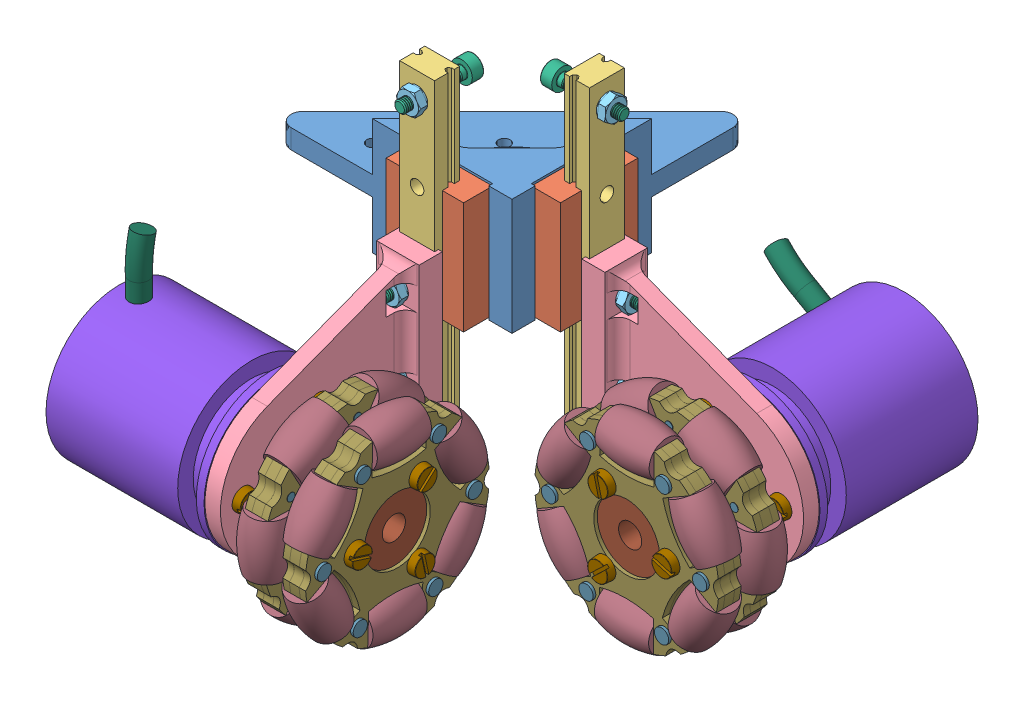
SolidWorks assembly 总体装配1, configuration 默认. Lengths in mm.
Overall size (140.92 111.21 136.4).
119 component instances, 15 part files, 118 mates.
Components (placement in the parent):
- 机架SLDPRT-1: 机架SLDPRT [默认] at (33.577 -2.0729 87.0624) size (60.04 30 60.04)
- 滑块-1: 滑块 [默认] at (40.077 -14.0229 81.0624) x (0 1 0) z (0 0 1) size (28.9 7.5 20)
- 滑块-2: 滑块 [默认] at (7.577 -14.0229 93.5624) x (0 1 0) z (-1 0 0) size (28.9 7.5 20)
- 滑轨-1: 滑轨 [默认] at (17.577 -49.5817 95.5624) size (9 90 6.5)
- 滑轨-2: 滑轨 [默认] at (42.077 -51.1888 71.0624) x (0 0 -1) z (1 0 0) size (9 90 6.5)
- 连接片-1: 连接片 [默认] at (19.577 -30.8137 129.5624) x (0 0 1) z (0 -1 0) size (53.77 11 52.41)
- 连接片-2: 连接片 [默认] at (76.077 -32.4209 69.0624) x (1 0 0) z (0 -1 0) size (53.77 11 52.41)
- hex nut style 1 gradeab_iso-1: hex nut style 1 gradeab_iso [ISO - 4032 - M3 - W - N] at (17.577 -45.5817 102.9624) x (-0.883653 0.468143 0) z (0 0 1) size (5.5 6.35 2.4)
- socket head cap screw_iso-3: socket head cap screw_iso [ISO 4762 M3 x 12 - 12S] at (17.577 -25.5817 89.5624) x (0 0 1) z (0.159835 -0.987144 0) size (15 5.5 5.5)
- socket head cap screw_iso-5: socket head cap screw_iso [ISO 4762 M3 x 12 - 12S] at (17.577 -5.5817 89.5624) x (0 0 1) z (0.284229 -0.958757 0) size (15 5.5 5.5)
- socket head cap screw_iso-9: socket head cap screw_iso [ISO 4762 M3 x 12 - 12S] at (36.077 -27.1888 71.0624) x (1 0 0) z (0 -0.834413 -0.551139) size (15 5.5 5.5)
- socket head cap screw_iso-11: socket head cap screw_iso [ISO 4762 M3 x 12 - 12S] at (36.077 -7.1888 71.0624) x (1 0 0) z (0 -0.855064 -0.518522) size (15 5.5 5.5)
- hex nut style 1 gradeab_iso-2: hex nut style 1 gradeab_iso [ISO - 4032 - M3 - W - N] at (17.577 -25.5817 102.9624) x (0 -1 0) z (0 0 1) size (5.5 6.35 2.4)
- hex nut style 1 gradeab_iso-4: hex nut style 1 gradeab_iso [ISO - 4032 - M3 - W - N] at (17.577 -5.5817 102.9624) x (0 -1 0) z (0 0 1) size (5.5 6.35 2.4)
- hex nut style 1 gradeab_iso-6: hex nut style 1 gradeab_iso [ISO - 4032 - M3 - W - N] at (49.477 -7.1888 71.0624) x (0 0.5 -0.866025) z (1 0 0) size (5.5 6.35 2.4)
- hex nut style 1 gradeab_iso-8: hex nut style 1 gradeab_iso [ISO - 4032 - M3 - W - N] at (49.477 -27.1888 71.0624) x (0 0.5 -0.866025) z (1 0 0) size (5.5 6.35 2.4)
- hex nut style 1 gradeab_iso-11: hex nut style 1 gradeab_iso [ISO - 4032 - M3 - W - N] at (49.477 -47.1888 71.0624) x (0 0.5 -0.866025) z (1 0 0) size (5.5 6.35 2.4)
- socket set screw cone point_iso-2: socket set screw cone point_iso [ISO 4027 - M4 x 4-N] at (27.077 -24.3164 129.375) x (0 -0.999584 0.028835) z (0.266634 -0.027791 -0.963397) size (4 4 4)
- socket set screw cone point_iso-3: socket set screw cone point_iso [ISO 4027 - M4 x 4-N] at (70.4593 -29.151 80.5624) x (0.864249 -0.503064 0) z (0.099801 0.171456 -0.980124) size (4 4 4)
- socket head cap screw_iso-13: socket head cap screw_iso [ISO 4762 M3 x 16 - 16S] at (32.577 -47.1888 71.0624) x (1 0 0) z (0 -0.325683 0.945479) size (19 5.5 5.5)
- hex nut style 1 gradeab_iso-13: hex nut style 1 gradeab_iso [ISO - 4032 - M3 - W - N] at (36.677 -47.1888 71.0624) x (0 -0.95795 0.286936) z (-1 0 0) size (5.5 6.35 2.4)
- hex nut style 1 gradeab_iso-15: hex nut style 1 gradeab_iso [ISO - 4032 - M3 - W - N] at (17.577 -45.5817 90.1624) x (-0.5 0.866025 0) z (0 0 -1) size (5.5 6.35 2.4)
- socket head cap screw_iso-14: socket head cap screw_iso [ISO 4762 M3 x 16 - 16S] at (17.577 -45.5817 86.0624) x (0 0 1) z (-0.77707 -0.629414 0) size (19 5.5 5.5)
- socket head cap screw_iso-16: socket head cap screw_iso [ISO 4762 M3 x 6 - 6S] at (23.577 5.4271 63.5624) x (1 0 0) z (0 0.484775 0.874639) size (9 5.5 5.5)
- socket head cap screw_iso-17: socket head cap screw_iso [ISO 4762 M3 x 6 - 6S] at (25.577 5.4271 78.5624) x (1 0 0) z (0 0.339966 0.940438) size (9 5.5 5.5)
- socket head cap screw_iso-21: socket head cap screw_iso [ISO 4762 M3 x 6 - 6S] at (25.577 -4.5729 63.5624) x (1 0 0) z (0 0.125522 0.992091) size (9 5.5 5.5)
- socket head cap screw_iso-23: socket head cap screw_iso [ISO 4762 M3 x 6 - 6S] at (10.077 5.4271 77.0624) x (0 0 1) z (-0.629289 -0.777171 0) size (9 5.5 5.5)
- socket head cap screw_iso-25: socket head cap screw_iso [ISO 4762 M3 x 6 - 6S] at (10.077 -4.5729 79.0624) x (0 0 1) z (-0.32553 -0.945532 0) size (9 5.5 5.5)
- socket head cap screw_iso-27: socket head cap screw_iso [ISO 4762 M3 x 6 - 6S] at (25.077 -4.5729 79.0624) x (0 0 1) z (0.017492 -0.999847 0) size (9 5.5 5.5)
- hex nut style 1 gradeab_iso-17: hex nut style 1 gradeab_iso [ISO - 4032 - M3 - W - N] at (17.577 34.4183 97.9624) x (-0.846539 -0.532326 0) z (0 0 1) size (5.5 6.35 2.4)
- hex nut style 1 gradeab_iso-19: hex nut style 1 gradeab_iso [ISO - 4032 - M3 - W - N] at (17.577 34.4183 90.1624) x (0.675882 -0.73701 0) z (0 0 -1) size (5.5 6.35 2.4)
- hex nut style 1 gradeab_iso-21: hex nut style 1 gradeab_iso [ISO - 4032 - M3 - W - N] at (36.677 32.8112 71.0624) x (0 -0.87174 0.489968) z (-1 0 0) size (5.5 6.35 2.4)
- hex nut style 1 gradeab_iso-23: hex nut style 1 gradeab_iso [ISO - 4032 - M3 - W - N] at (44.477 32.8112 71.0624) x (0 0.818224 -0.574899) z (1 0 0) size (5.5 6.35 2.4)
- socket head cap screw_iso-31: socket head cap screw_iso [ISO 4762 M3 x 16 - 16S] at (17.577 34.4183 81.0624) x (0 0 1) z (-0.514934 -0.85723 0) size (19 5.5 5.5)
- socket head cap screw_iso-33: socket head cap screw_iso [ISO 4762 M3 x 16 - 16S] at (27.577 32.8112 71.0624) x (1 0 0) z (0 -0.968527 0.248907) size (19 5.5 5.5)
- 编码器1-4: 编码器1 [默认] at (-25.223 -30.8137 129.5624) x (0 0 1) z (0 1 0) size (38 40.8 38)
- 编码器1-5: 编码器1 [默认] at (76.077 -32.4209 28.2624) x (-0.5 -0.866025 0) z (-0.866025 0.5 0) size (38 40.8 38)
- slotted cheese head screw_iso-1: slotted cheese head screw_iso [ISO 1207 - M3 x 8 - 8N] at (89.077 -32.4209 75.0624) x (0 0 -1) z (1 0 0) size (10.01 5.5 5.5)
- slotted cheese head screw_iso-2: slotted cheese head screw_iso [ISO 1207 - M3 x 8 - 8N] at (69.577 -21.1626 75.0624) x (0 0 -1) z (-0.5 0.866025 0) size (10.01 5.5 5.5)
- slotted cheese head screw_iso-3: slotted cheese head screw_iso [ISO 1207 - M3 x 8 - 8N] at (69.577 -43.6792 75.0624) x (0 0 -1) z (-0.5 -0.866025 0) size (10.01 5.5 5.5)
- slotted cheese head screw_iso-4: slotted cheese head screw_iso [ISO 1207 - M3 x 8 - 8N] at (21.577 -30.8137 142.5624) x (-1 0 0) z (0 0.285358 -0.958421) size (10.01 5.5 5.5)
- slotted cheese head screw_iso-6: slotted cheese head screw_iso [ISO 1207 - M3 x 8 - 8N] at (21.577 -42.0721 123.0624) x (-1 0 0) z (0 0.687338 0.726338) size (10.01 5.5 5.5)
- slotted cheese head screw_iso-7: slotted cheese head screw_iso [ISO 1207 - M3 x 8 - 8N] at (21.577 -19.5554 123.0624) x (-1 0 0) z (0 -0.972696 0.232083) size (10.01 5.5 5.5)
- 轴-1: 轴 [默认] at (10.577 -30.8137 129.5624) x (0 0.028835 0.999584) z (0 0.999584 -0.028835) size (6 25 6)
- 轴-3: 轴 [默认] at (76.077 -32.4209 64.0624) x (-0.503064 -0.864249 0) z (-0.864249 0.503064 0) size (6 25 6)
- 2寸全向轮1-4: 2寸全向轮1 [默认] at (34.6002 -32.645 101.6036) x (0 0.999584 -0.028835) z (0 0.028835 0.999584) size (65.85 26.41 65.85)
  - 法兰（新）-1: 法兰（新） [默认] at (1.0243 -5.9767 28) size (28 22 28)
  - 2mm全向轮-1: 2mm全向轮 [默认] at (11.1029 12.5733 31.6277) x (0.866025 0 0.5) z (0 1 0) size (52.67 52.62 13.52)
    - 2mm全向轮片1-1: 2mm全向轮片1 [默认] at (-10.5422 -1.8976 -13.55) x (0 -1 0) z (0 0 1) size (47.34 45.39 5.9)
    - 从动-1: 从动 [默认] at (-10.1553 -1.8976 -5.0249) x (0 -1 0) z (0.265082 0 0.964226) size (14 11 11)
    - 从动-13: 从动 [默认] at (-10.3488 -2.2327 -5.0249) x (-0.866025 -0.5 0) z (0.132541 -0.229568 0.964226) size (14 11 11)
    - 从动-14: 从动 [默认] at (-10.7357 -2.2327 -5.0249) x (-0.866025 0.5 0) z (-0.132541 -0.229568 0.964226) size (14 11 11)
    - 从动-15: 从动 [默认] at (-10.9291 -1.8976 -5.0249) x (0 1 0) z (-0.265082 0 0.964226) size (14 11 11)
    - 从动-16: 从动 [默认] at (-10.7357 -1.5625 -5.0249) x (0.866025 0.5 0) z (-0.132541 0.229568 0.964226) size (14 11 11)
    - 从动-17: 从动 [默认] at (-10.3488 -1.5625 -5.0249) x (0.866025 -0.5 0) z (0.132541 0.229568 0.964226) size (14 11 11)
  - 2mm全向轮-2: 2mm全向轮 [默认] at (7.9388 1.6733 36.181) x (0.5 0 0.866025) z (0 1 0) size (52.67 52.62 13.52)
    - 2mm全向轮片1-1: 2mm全向轮片1 [默认] at (-10.5422 -1.8976 -13.55) x (0 -1 0) z (0 0 1) size (47.34 45.39 5.9)
    - 从动-1: 从动 [默认] at (-10.1553 -1.8976 -5.0249) x (0 -1 0) z (0.265082 0 0.964226) size (14 11 11)
    - 从动-13: 从动 [默认] at (-10.3488 -2.2327 -5.0249) x (-0.866025 -0.5 0) z (0.132541 -0.229568 0.964226) size (14 11 11)
    - 从动-14: 从动 [默认] at (-10.7357 -2.2327 -5.0249) x (-0.866025 0.5 0) z (-0.132541 -0.229568 0.964226) size (14 11 11)
    - 从动-15: 从动 [默认] at (-10.9291 -1.8976 -5.0249) x (0 1 0) z (-0.265082 0 0.964226) size (14 11 11)
    - 从动-16: 从动 [默认] at (-10.7357 -1.5625 -5.0249) x (0.866025 0.5 0) z (-0.132541 0.229568 0.964226) size (14 11 11)
    - 从动-17: 从动 [默认] at (-10.3488 -1.5625 -5.0249) x (0.866025 -0.5 0) z (0.132541 0.229568 0.964226) size (14 11 11)
  - thin head rivets gb-1: thin head rivets gb [GB_CONNECTING_PIECE_RIVET_THR 2X6] at (17.9118 -12.5567 18.25) x (0 1 0) z (-0.99315 0 -0.116849) size (6.68 3.74 3.74)
  - thin head rivets gb-3: thin head rivets gb [GB_CONNECTING_PIECE_RIVET_THR 2X6] at (17.9118 -12.5567 37.75) x (0 1 0) z (-0.395381 0 -0.918517) size (6.68 3.74 3.74)
  - thin head rivets gb-4: thin head rivets gb [GB_CONNECTING_PIECE_RIVET_THR 2X6] at (1.0243 -12.5567 47.5) x (0 1 0) z (0.597769 0 -0.801668) size (6.68 3.74 3.74)
  - thin head rivets gb-5: thin head rivets gb [GB_CONNECTING_PIECE_RIVET_THR 2X6] at (-15.8632 -12.5567 37.75) x (0 1 0) z (0.99315 0 0.116849) size (6.68 3.74 3.74)
  - thin head rivets gb-6: thin head rivets gb [GB_CONNECTING_PIECE_RIVET_THR 2X6] at (-15.8632 -12.5567 18.25) x (0 1 0) z (0.395381 0 0.918517) size (6.68 3.74 3.74)
  - thin head rivets gb-7: thin head rivets gb [GB_CONNECTING_PIECE_RIVET_THR 2X6] at (1.0243 -12.5567 8.5) x (0 1 0) z (-0.597769 0 0.801668) size (6.68 3.74 3.74)
  - thin head rivets gb-9: thin head rivets gb [GB_CONNECTING_PIECE_RIVET_THR 2X6] at (-18.4757 5.6033 28) x (0 -1 0) z (-0.795368 0 -0.606127) size (6.68 3.74 3.74)
  - thin head rivets gb-11: thin head rivets gb [GB_CONNECTING_PIECE_RIVET_THR 2X6] at (-8.7257 5.6033 11.1125) x (0 -1 0) z (0.127237 0 -0.991872) size (6.68 3.74 3.74)
  - thin head rivets gb-12: thin head rivets gb [GB_CONNECTING_PIECE_RIVET_THR 2X6] at (10.7743 5.6033 11.1125) x (0 -1 0) z (0.922605 0 -0.385745) size (6.68 3.74 3.74)
  - thin head rivets gb-13: thin head rivets gb [GB_CONNECTING_PIECE_RIVET_THR 2X6] at (20.5243 5.6033 28) x (0 -1 0) z (0.795368 0 0.606127) size (6.68 3.74 3.74)
  - thin head rivets gb-14: thin head rivets gb [GB_CONNECTING_PIECE_RIVET_THR 2X6] at (10.7743 5.6033 44.8875) x (0 -1 0) z (-0.127237 0 0.991872) size (6.68 3.74 3.74)
  - thin head rivets gb-15: thin head rivets gb [GB_CONNECTING_PIECE_RIVET_THR 2X6] at (-8.7257 5.6033 44.8875) x (0 -1 0) z (-0.922605 0 0.385745) size (6.68 3.74 3.74)
  - slotted cheese head screw_iso-1: slotted cheese head screw_iso [ISO 1207 - M3 x 10 - 10N] at (6.5243 6.9233 18.4737) x (0 -1 0) z (0 0 1) size (12.01 5.5 5.5)
  - slotted cheese head screw_iso-2: slotted cheese head screw_iso [ISO 1207 - M3 x 10 - 10N] at (6.5243 6.9233 37.5263) x (0 -1 0) z (-0.866025 0 -0.5) size (12.01 5.5 5.5)
  - slotted cheese head screw_iso-3: slotted cheese head screw_iso [ISO 1207 - M3 x 10 - 10N] at (-9.9757 6.9233 28) x (0 -1 0) z (0.866025 0 -0.5) size (12.01 5.5 5.5)
  - slotted cheese head screw_iso-4: slotted cheese head screw_iso [ISO 1207 - M3 x 10 - 10N] at (10.5506 -13.8767 22.5) x (0 1 0) z (0.694913 0 -0.719094) size (12.01 5.5 5.5)
  - slotted cheese head screw_iso-6: slotted cheese head screw_iso [ISO 1207 - M3 x 10 - 10N] at (1.0243 -13.8767 39) x (0 1 0) z (0.275298 0 0.961359) size (12.01 5.5 5.5)
  - slotted cheese head screw_iso-7: slotted cheese head screw_iso [ISO 1207 - M3 x 10 - 10N] at (-8.502 -13.8767 22.5) x (0 1 0) z (-0.97021 0 -0.242265) size (12.01 5.5 5.5)
- 2寸全向轮1-5: 2寸全向轮1 [默认] at (91.048 -8.7372 88.0857) x (-0.864249 0.503064 0) z (-0.503064 -0.864249 0) size (65.85 26.41 65.85)
  - 法兰（新）-1: 法兰（新） [默认] at (1.0243 -5.9767 28) size (28 22 28)
  - 2mm全向轮-1: 2mm全向轮 [默认] at (11.1029 12.5733 31.6277) x (0.866025 0 0.5) z (0 1 0) size (52.67 52.62 13.52)
    - 2mm全向轮片1-1: 2mm全向轮片1 [默认] at (-10.5422 -1.8976 -13.55) x (0 -1 0) z (0 0 1) size (47.34 45.39 5.9)
    - 从动-1: 从动 [默认] at (-10.1553 -1.8976 -5.0249) x (0 -1 0) z (0.265082 0 0.964226) size (14 11 11)
    - 从动-13: 从动 [默认] at (-10.3488 -2.2327 -5.0249) x (-0.866025 -0.5 0) z (0.132541 -0.229568 0.964226) size (14 11 11)
    - 从动-14: 从动 [默认] at (-10.7357 -2.2327 -5.0249) x (-0.866025 0.5 0) z (-0.132541 -0.229568 0.964226) size (14 11 11)
    - 从动-15: 从动 [默认] at (-10.9291 -1.8976 -5.0249) x (0 1 0) z (-0.265082 0 0.964226) size (14 11 11)
    - 从动-16: 从动 [默认] at (-10.7357 -1.5625 -5.0249) x (0.866025 0.5 0) z (-0.132541 0.229568 0.964226) size (14 11 11)
    - 从动-17: 从动 [默认] at (-10.3488 -1.5625 -5.0249) x (0.866025 -0.5 0) z (0.132541 0.229568 0.964226) size (14 11 11)
  - 2mm全向轮-2: 2mm全向轮 [默认] at (7.9388 1.6733 36.181) x (0.5 0 0.866025) z (0 1 0) size (52.67 52.62 13.52)
    - 2mm全向轮片1-1: 2mm全向轮片1 [默认] at (-10.5422 -1.8976 -13.55) x (0 -1 0) z (0 0 1) size (47.34 45.39 5.9)
    - 从动-1: 从动 [默认] at (-10.1553 -1.8976 -5.0249) x (0 -1 0) z (0.265082 0 0.964226) size (14 11 11)
    - 从动-13: 从动 [默认] at (-10.3488 -2.2327 -5.0249) x (-0.866025 -0.5 0) z (0.132541 -0.229568 0.964226) size (14 11 11)
    - 从动-14: 从动 [默认] at (-10.7357 -2.2327 -5.0249) x (-0.866025 0.5 0) z (-0.132541 -0.229568 0.964226) size (14 11 11)
    - 从动-15: 从动 [默认] at (-10.9291 -1.8976 -5.0249) x (0 1 0) z (-0.265082 0 0.964226) size (14 11 11)
    - 从动-16: 从动 [默认] at (-10.7357 -1.5625 -5.0249) x (0.866025 0.5 0) z (-0.132541 0.229568 0.964226) size (14 11 11)
    - 从动-17: 从动 [默认] at (-10.3488 -1.5625 -5.0249) x (0.866025 -0.5 0) z (0.132541 0.229568 0.964226) size (14 11 11)
  - thin head rivets gb-1: thin head rivets gb [GB_CONNECTING_PIECE_RIVET_THR 2X6] at (17.9118 -12.5567 18.25) x (0 1 0) z (-0.99315 0 -0.116849) size (6.68 3.74 3.74)
  - thin head rivets gb-3: thin head rivets gb [GB_CONNECTING_PIECE_RIVET_THR 2X6] at (17.9118 -12.5567 37.75) x (0 1 0) z (-0.395381 0 -0.918517) size (6.68 3.74 3.74)
  - thin head rivets gb-4: thin head rivets gb [GB_CONNECTING_PIECE_RIVET_THR 2X6] at (1.0243 -12.5567 47.5) x (0 1 0) z (0.597769 0 -0.801668) size (6.68 3.74 3.74)
  - thin head rivets gb-5: thin head rivets gb [GB_CONNECTING_PIECE_RIVET_THR 2X6] at (-15.8632 -12.5567 37.75) x (0 1 0) z (0.99315 0 0.116849) size (6.68 3.74 3.74)
  - thin head rivets gb-6: thin head rivets gb [GB_CONNECTING_PIECE_RIVET_THR 2X6] at (-15.8632 -12.5567 18.25) x (0 1 0) z (0.395381 0 0.918517) size (6.68 3.74 3.74)
  - thin head rivets gb-7: thin head rivets gb [GB_CONNECTING_PIECE_RIVET_THR 2X6] at (1.0243 -12.5567 8.5) x (0 1 0) z (-0.597769 0 0.801668) size (6.68 3.74 3.74)
  - thin head rivets gb-9: thin head rivets gb [GB_CONNECTING_PIECE_RIVET_THR 2X6] at (-18.4757 5.6033 28) x (0 -1 0) z (-0.795368 0 -0.606127) size (6.68 3.74 3.74)
  - thin head rivets gb-11: thin head rivets gb [GB_CONNECTING_PIECE_RIVET_THR 2X6] at (-8.7257 5.6033 11.1125) x (0 -1 0) z (0.127237 0 -0.991872) size (6.68 3.74 3.74)
  - thin head rivets gb-12: thin head rivets gb [GB_CONNECTING_PIECE_RIVET_THR 2X6] at (10.7743 5.6033 11.1125) x (0 -1 0) z (0.922605 0 -0.385745) size (6.68 3.74 3.74)
  - thin head rivets gb-13: thin head rivets gb [GB_CONNECTING_PIECE_RIVET_THR 2X6] at (20.5243 5.6033 28) x (0 -1 0) z (0.795368 0 0.606127) size (6.68 3.74 3.74)
  - thin head rivets gb-14: thin head rivets gb [GB_CONNECTING_PIECE_RIVET_THR 2X6] at (10.7743 5.6033 44.8875) x (0 -1 0) z (-0.127237 0 0.991872) size (6.68 3.74 3.74)
  - thin head rivets gb-15: thin head rivets gb [GB_CONNECTING_PIECE_RIVET_THR 2X6] at (-8.7257 5.6033 44.8875) x (0 -1 0) z (-0.922605 0 0.385745) size (6.68 3.74 3.74)
  - slotted cheese head screw_iso-1: slotted cheese head screw_iso [ISO 1207 - M3 x 10 - 10N] at (6.5243 6.9233 18.4737) x (0 -1 0) z (0 0 1) size (12.01 5.5 5.5)
  - slotted cheese head screw_iso-2: slotted cheese head screw_iso [ISO 1207 - M3 x 10 - 10N] at (6.5243 6.9233 37.5263) x (0 -1 0) z (-0.866025 0 -0.5) size (12.01 5.5 5.5)
  - slotted cheese head screw_iso-3: slotted cheese head screw_iso [ISO 1207 - M3 x 10 - 10N] at (-9.9757 6.9233 28) x (0 -1 0) z (0.866025 0 -0.5) size (12.01 5.5 5.5)
  - slotted cheese head screw_iso-4: slotted cheese head screw_iso [ISO 1207 - M3 x 10 - 10N] at (10.5506 -13.8767 22.5) x (0 1 0) z (0.694913 0 -0.719094) size (12.01 5.5 5.5)
  - slotted cheese head screw_iso-6: slotted cheese head screw_iso [ISO 1207 - M3 x 10 - 10N] at (1.0243 -13.8767 39) x (0 1 0) z (0.275298 0 0.961359) size (12.01 5.5 5.5)
  - slotted cheese head screw_iso-7: slotted cheese head screw_iso [ISO 1207 - M3 x 10 - 10N] at (-8.502 -13.8767 22.5) x (0 1 0) z (-0.97021 0 -0.242265) size (12.01 5.5 5.5)
- 电线-1: 电线 [默认] at (-20.223 -13.8137 129.5624) x (0 1 0) z (0 0 1) size (17.03 5 5.95)
- 电线-2: 电线 [默认] at (61.3545 -23.9209 33.2624) x (-0.866025 0.5 0) z (0.046757 0.080985 0.995618) size (17.03 5 5.95)
Mates (geometry in assembly coordinates):
- 同心1: concentric anti-aligned: cylinder of 机架SLDPRT-1 through (24.3343 5.4271 78.5624) axis (1 0 0) radius 1.5; cylinder of 滑块-1 through (35.577 5.4271 78.5624) axis (-1 0 0) radius 1.5
- 同心2: concentric anti-aligned: cylinder of 机架SLDPRT-1 through (24.3343 5.4271 63.5624) axis (1 0 0) radius 1.5; cylinder of 滑块-1 through (35.577 5.4271 63.5624) axis (-1 0 0) radius 1.5
- 重合1: coincident anti-aligned: plane of 机架SLDPRT-1 through (32.577 -2.0729 87.0624) normal (1 0 0); plane of 滑块-1 through (32.577 -14.0229 81.0624) normal (-1 0 0)
- 同心3: concentric anti-aligned: cylinder of 机架SLDPRT-1 through (10.077 5.4271 77.8198) axis (0 0 1) radius 1.5; cylinder of 滑块-2 through (10.077 5.4271 89.0624) axis (0 0 -1) radius 1.5
- 同心4: concentric anti-aligned: cylinder of 机架SLDPRT-1 through (25.077 5.4271 77.8198) axis (0 0 1) radius 1.5; cylinder of 滑块-2 through (25.077 5.4271 89.0624) axis (0 0 -1) radius 1.5
- 重合2: coincident anti-aligned: plane of 机架SLDPRT-1 through (33.577 -2.0729 86.0624) normal (0 0 1); plane of 滑块-2 through (7.577 -14.0229 86.0624) normal (0 0 -1)
- 重合3: coincident anti-aligned: plane of 滑块-2 through (13.077 -14.0229 89.0624) normal (0 0 1); plane of 滑轨-1 through (22.077 40.4183 89.0624) normal (0 0 -1)
- 重合4: coincident anti-aligned: plane of 滑块-2 through (13.077 -14.0229 93.5624) normal (1 0 0); plane of 滑轨-1 through (13.077 40.4183 95.5624) normal (-1 0 0)
- 重合5: coincident anti-aligned: plane of 滑块-1 through (35.577 -14.0229 75.5624) normal (1 0 0); plane of 滑轨-2 through (35.577 38.8112 66.5624) normal (-1 0 0)
- 重合6: coincident anti-aligned: plane of 滑块-1 through (40.077 -14.0229 75.5624) normal (0 0 -1); plane of 滑轨-2 through (42.077 38.8112 75.5624) normal (0 0 1)
- 重合7: coincident anti-aligned: plane of 滑轨-1 through (17.577 40.4183 95.5624) normal (0 0 1); plane of 连接片-1 through (15.577 -49.5817 95.5624) normal (0 0 -1)
- 同心5: concentric aligned: cylinder of 滑轨-1 through (17.577 -5.5817 99.0624) axis (0 0 -1) radius 1.75; cylinder of 连接片-1 through (17.577 -5.5817 104.8051) axis (0 0 -1) radius 1.5
- 同心6: concentric aligned: cylinder of 滑轨-1 through (17.577 -45.5817 99.0624) axis (0 0 -1) radius 1.75; cylinder of 连接片-1 through (17.577 -45.5817 104.8051) axis (0 0 -1) radius 1.5
- 重合8: coincident anti-aligned: plane of 滑轨-2 through (42.077 38.8112 71.0624) normal (1 0 0); plane of 连接片-2 through (42.077 -51.1888 73.0624) normal (-1 0 0)
- 同心7: concentric aligned: cylinder of 滑轨-2 through (45.577 -7.1888 71.0624) axis (-1 0 0) radius 1.75; cylinder of 连接片-2 through (51.3196 -7.1888 71.0624) axis (-1 0 0) radius 1.5
- 同心8: concentric aligned: cylinder of 滑轨-2 through (45.577 -47.1888 71.0624) axis (-1 0 0) radius 1.75; cylinder of 连接片-2 through (51.3196 -47.1888 71.0624) axis (-1 0 0) radius 1.5
- 同心9: concentric anti-aligned: cylinder of 连接片-1 through (15.577 -6.3549 129.5624) axis (1 0 0) radius 4; cylinder of ? through (35.577 -6.3549 129.5624) axis (-1 0 0) radius 3
- 同心10: concentric aligned: cylinder of 连接片-1 through (15.577 7.9034 123.0624) axis (1 0 0) radius 1.5; cylinder of ? through (8.577 7.9034 123.0624) axis (1 0 0) radius 1.5
- 重合9: coincident anti-aligned: plane of 连接片-1 through (15.577 -3.3549 129.5624) normal (-1 0 0); plane of ? through (15.577 -3.3549 129.5624) normal (1 0 0)
- 同心11: concentric aligned: cylinder of 连接片-2 through (76.077 -55.3549 73.0624) axis (0 0 -1) radius 4; cylinder of ? through (76.077 -55.3549 89.0624) axis (0 0 -1) radius 3
- 同心12: concentric anti-aligned: cylinder of 连接片-2 through (69.577 6.3098 73.0624) axis (0 0 -1) radius 1.5; cylinder of ? through (69.577 6.3098 62.0624) axis (0 0 1) radius 1.5
- 重合10: coincident anti-aligned: plane of 连接片-2 through (76.077 -4.9485 69.0624) normal (0 0 -1); plane of ? through (76.077 -4.9485 69.0624) normal (0 0 1)
- 同心13: concentric anti-aligned: cylinder of ? through (35.577 -6.3549 129.5624) axis (-1 0 0) radius 3; cylinder of ? through (23.577 -6.3549 129.5624) axis (1 0 0) radius 3
- 距离1: distance = 4 mm anti-aligned: plane of ? through (23.577 -3.3549 129.5624) normal (-1 0 0); plane of 连接片-1 through (19.577 -3.3549 129.5624) normal (1 0 0)
- 同心14: concentric anti-aligned: cylinder of ? through (76.077 -55.3549 89.0624) axis (0 0 -1) radius 3; cylinder of ? through (76.077 -55.3549 77.0624) axis (0 0 1) radius 3
- 距离2: distance = 4 mm anti-aligned: plane of ? through (76.077 -4.9485 77.0624) normal (0 0 -1); plane of 连接片-2 through (76.077 -4.9485 73.0624) normal (0 0 1)
- 同心15: concentric aligned: cylinder of 滑轨-1 through (17.577 -122.6452 99.0624) axis (0 0 -1) radius 1.75; cylinder of ? through (17.577 -122.6452 57.8124) axis (0 0 -1) radius 1.5
- 重合12: coincident anti-aligned: plane of 滑轨-1 through (17.577 -122.6452 92.5624) normal (0 0 -1); plane of ? through (14.827 -122.6487 92.5624) normal (0 0 1)
- 同心16: concentric anti-aligned: cylinder of 连接片-1 through (17.577 -45.5817 104.8051) axis (0 0 -1) radius 1.5; cylinder of hex nut style 1 gradeab_iso-1 through (17.577 -45.5817 100.5624) axis (0 0 1) radius 1.25
- 重合13: coincident anti-aligned: plane of 连接片-1 through (19.577 -30.8137 100.5624) normal (0 0 1); plane of hex nut style 1 gradeab_iso-1 through (16.0904 -48.3877 100.5624) normal (0 0 -1)
- 同心18: concentric aligned: cylinder of 滑轨-1 through (17.577 -25.5817 99.0624) axis (0 0 -1) radius 1.75; cylinder of socket head cap screw_iso-3 through (17.577 -25.5817 57.8124) axis (0 0 -1) radius 1.5
- 重合14: coincident anti-aligned: circle of 滑轨-1; plane of socket head cap screw_iso-3 through (14.8623 -26.0212 92.5624) normal (0 0 1)
- 同心19: concentric aligned: cylinder of 滑轨-1 through (17.577 -5.5817 99.0624) axis (0 0 -1) radius 1.75; cylinder of socket head cap screw_iso-5 through (17.577 -5.5817 57.8124) axis (0 0 -1) radius 1.5
- 重合15: coincident anti-aligned: plane of 滑轨-1 through (17.577 -5.5817 92.5624) normal (0 0 -1); plane of socket head cap screw_iso-5 through (14.9404 -6.3633 92.5624) normal (0 0 1)
- 同心20: concentric aligned: cylinder of 滑轨-2 through (45.577 -111.9175 71.0624) axis (-1 0 0) radius 1.75; cylinder of ? through (4.327 -111.9175 71.0624) axis (-1 0 0) radius 1.5
- 重合16: coincident anti-aligned: plane of 滑轨-2 through (39.077 -111.9175 71.0624) normal (-1 0 0); plane of ? through (39.077 -113.3861 73.3875) normal (1 0 0)
- 同心21: concentric aligned: cylinder of 滑轨-2 through (45.577 -27.1888 71.0624) axis (-1 0 0) radius 1.75; cylinder of socket head cap screw_iso-9 through (4.327 -27.1888 71.0624) axis (-1 0 0) radius 1.5
- 重合17: coincident anti-aligned: plane of 滑轨-2 through (39.077 -27.1888 71.0624) normal (-1 0 0); plane of socket head cap screw_iso-9 through (39.077 -28.7045 73.3571) normal (1 0 0)
- 同心22: concentric aligned: cylinder of 滑轨-2 through (45.577 -7.1888 71.0624) axis (-1 0 0) radius 1.75; cylinder of socket head cap screw_iso-11 through (4.327 -7.1888 71.0624) axis (-1 0 0) radius 1.5
- 重合18: coincident anti-aligned: plane of 滑轨-2 through (39.077 -7.1888 71.0624) normal (-1 0 0); plane of socket head cap screw_iso-11 through (39.077 -8.6148 73.4139) normal (1 0 0)
- 同心23: concentric anti-aligned: cylinder of 连接片-1 through (17.577 -25.5817 104.8051) axis (0 0 -1) radius 1.5; cylinder of hex nut style 1 gradeab_iso-2 through (17.577 -25.5817 100.5624) axis (0 0 1) radius 1.25
- 重合19: coincident anti-aligned: plane of 连接片-1 through (19.577 -30.8137 100.5624) normal (0 0 1); plane of hex nut style 1 gradeab_iso-2 through (20.7524 -25.5817 100.5624) normal (0 0 -1)
- 同心24: concentric anti-aligned: cylinder of 连接片-1 through (17.577 -5.5817 104.8051) axis (0 0 -1) radius 1.5; cylinder of hex nut style 1 gradeab_iso-4 through (17.577 -5.5817 100.5624) axis (0 0 1) radius 1.25
- 重合20: coincident anti-aligned: plane of 连接片-1 through (19.577 -30.8137 100.5624) normal (0 0 1); plane of hex nut style 1 gradeab_iso-4 through (20.7524 -5.5817 100.5624) normal (0 0 -1)
- 同心25: concentric anti-aligned: cylinder of 连接片-2 through (51.3196 -7.1888 71.0624) axis (-1 0 0) radius 1.5; cylinder of hex nut style 1 gradeab_iso-6 through (47.077 -7.1888 71.0624) axis (1 0 0) radius 1.25
- 重合21: coincident anti-aligned: plane of 连接片-2 through (47.077 -32.4209 69.0624) normal (1 0 0); plane of hex nut style 1 gradeab_iso-6 through (47.077 -4.4388 72.6502) normal (-1 0 0)
- 同心26: concentric anti-aligned: cylinder of 连接片-2 through (51.3196 -27.1888 71.0624) axis (-1 0 0) radius 1.5; cylinder of hex nut style 1 gradeab_iso-8 through (47.077 -27.1888 71.0624) axis (1 0 0) radius 1.25
- 重合22: coincident anti-aligned: plane of 连接片-2 through (47.077 -32.4209 69.0624) normal (1 0 0); plane of hex nut style 1 gradeab_iso-8 through (47.077 -24.4388 72.6502) normal (-1 0 0)
- 同心28: concentric anti-aligned: cylinder of 连接片-2 through (51.3196 -47.1888 71.0624) axis (-1 0 0) radius 1.5; cylinder of hex nut style 1 gradeab_iso-11 through (47.077 -47.1888 71.0624) axis (1 0 0) radius 1.25
- 重合23: coincident anti-aligned: plane of 连接片-2 through (47.077 -32.4209 69.0624) normal (1 0 0); plane of hex nut style 1 gradeab_iso-11 through (47.077 -44.4388 72.6502) normal (-1 0 0)
- 平行5: parallel anti-aligned: plane of 连接片-2 through (52.077 -44.3272 61.2522) normal (0 -1 0); plane of hex nut style 1 gradeab_iso-11 through (47.077 -44.4388 69.4747) normal (0 1 0)
- 平行6: parallel anti-aligned: plane of 连接片-2 through (52.077 -24.3272 61.2522) normal (0 -1 0); plane of hex nut style 1 gradeab_iso-8 through (47.077 -24.4388 69.4747) normal (0 1 0)
- 平行7: parallel anti-aligned: plane of 连接片-2 through (52.077 -4.3272 61.2522) normal (0 -1 0); plane of hex nut style 1 gradeab_iso-6 through (47.077 -4.4388 69.4747) normal (0 1 0)
- 平行8: parallel anti-aligned: plane of 连接片-1 through (27.3872 -2.7201 105.5624) normal (0 -1 0); plane of hex nut style 1 gradeab_iso-4 through (19.1647 -2.8317 100.5624) normal (0 1 0)
- 平行9: parallel anti-aligned: plane of 连接片-1 through (27.3872 -22.7201 105.5624) normal (0 -1 0); plane of hex nut style 1 gradeab_iso-2 through (19.1647 -22.8317 100.5624) normal (0 1 0)
- 同心31: concentric aligned: cylinder of 滑轨-2 through (45.577 -47.1888 71.0624) axis (-1 0 0) radius 1.75; cylinder of hex nut style 1 gradeab_iso-13 through (39.077 -47.1888 71.0624) axis (-1 0 0) radius 1.25
- 重合32: coincident anti-aligned: plane of 滑轨-2 through (39.077 -47.1888 71.0624) normal (-1 0 0); plane of hex nut style 1 gradeab_iso-13 through (39.077 -46.2777 74.1043) normal (1 0 0)
- 同心32: concentric aligned: cylinder of 滑轨-1 through (17.577 -45.5817 99.0624) axis (0 0 -1) radius 1.75; cylinder of hex nut style 1 gradeab_iso-15 through (17.577 -45.5817 92.5624) axis (0 0 -1) radius 1.25
- 重合33: coincident anti-aligned: plane of 滑轨-1 through (17.577 -45.5817 92.5624) normal (0 0 -1); plane of hex nut style 1 gradeab_iso-15 through (20.327 -43.994 92.5624) normal (0 0 1)
- 同心33: concentric aligned: cylinder of socket head cap screw_iso-13 through (0.827 -47.1888 71.0624) axis (-1 0 0) radius 1.5; cylinder of hex nut style 1 gradeab_iso-13 through (39.077 -47.1888 71.0624) axis (-1 0 0) radius 1.25
- 重合35: coincident anti-aligned: plane of 滑轨-2 through (35.577 38.8112 66.5624) normal (-1 0 0); plane of socket head cap screw_iso-13 through (35.577 -44.5888 71.9581) normal (1 0 0)
- 同心34: concentric aligned: cylinder of hex nut style 1 gradeab_iso-15 through (17.577 -45.5817 92.5624) axis (0 0 -1) radius 1.25; cylinder of socket head cap screw_iso-14 through (17.577 -45.5817 54.3124) axis (0 0 -1) radius 1.5
- 重合36: coincident anti-aligned: plane of 滑轨-1 through (22.077 40.4183 89.0624) normal (0 0 -1); plane of socket head cap screw_iso-14 through (15.8461 -43.4448 89.0624) normal (0 0 1)
- 同心35: concentric anti-aligned: cylinder of 机架SLDPRT-1 through (24.3343 5.4271 63.5624) axis (1 0 0) radius 1.5; cylinder of socket head cap screw_iso-16 through (-8.173 5.4271 63.5624) axis (-1 0 0) radius 1.5
- 距离12: distance = 2 mm anti-aligned: plane of 机架SLDPRT-1 through (28.577 -2.0729 87.0624) normal (-1 0 0); plane of socket head cap screw_iso-16 through (26.577 7.8324 62.2293) normal (1 0 0)
- 同心36: concentric anti-aligned: cylinder of 机架SLDPRT-1 through (24.3343 5.4271 78.5624) axis (1 0 0) radius 1.5; cylinder of socket head cap screw_iso-17 through (-6.173 5.4271 78.5624) axis (-1 0 0) radius 1.5
- 重合38: coincident anti-aligned: plane of 机架SLDPRT-1 through (28.577 -2.0729 87.0624) normal (-1 0 0); plane of socket head cap screw_iso-17 through (28.577 8.0133 77.6275) normal (1 0 0)
- 重合39: coincident anti-aligned: plane of 机架SLDPRT-1 through (28.577 -2.0729 87.0624) normal (-1 0 0); plane of ? through (28.577 -1.8887 77.9645) normal (1 0 0)
- 同心38: concentric anti-aligned: cylinder of 机架SLDPRT-1 through (24.3343 -4.5729 63.5624) axis (1 0 0) radius 1.5; cylinder of socket head cap screw_iso-21 through (-6.173 -4.5729 63.5624) axis (-1 0 0) radius 1.5
- 重合40: coincident anti-aligned: plane of 机架SLDPRT-1 through (28.577 -2.0729 87.0624) normal (-1 0 0); plane of socket head cap screw_iso-21 through (28.577 -1.8446 63.2173) normal (1 0 0)
- 同心39: concentric anti-aligned: cylinder of 机架SLDPRT-1 through (10.077 5.4271 77.8198) axis (0 0 1) radius 1.5; cylinder of socket head cap screw_iso-23 through (10.077 5.4271 45.3124) axis (0 0 -1) radius 1.5
- 距离13: distance = 2 mm anti-aligned: plane of 机架SLDPRT-1 through (33.577 -2.0729 82.0624) normal (0 0 -1); plane of socket head cap screw_iso-23 through (7.9397 7.1577 80.0624) normal (0 0 1)
- 同心40: concentric anti-aligned: cylinder of 机架SLDPRT-1 through (10.077 -4.5729 77.8198) axis (0 0 1) radius 1.5; cylinder of socket head cap screw_iso-25 through (10.077 -4.5729 47.3124) axis (0 0 -1) radius 1.5
- 重合42: coincident anti-aligned: plane of 机架SLDPRT-1 through (33.577 -2.0729 82.0624) normal (0 0 -1); plane of socket head cap screw_iso-25 through (7.4767 -3.6777 82.0624) normal (0 0 1)
- 同心41: concentric anti-aligned: cylinder of 机架SLDPRT-1 through (25.077 -4.5729 77.8198) axis (0 0 1) radius 1.5; cylinder of socket head cap screw_iso-27 through (25.077 -4.5729 47.3124) axis (0 0 -1) radius 1.5
- 重合43: coincident anti-aligned: plane of 机架SLDPRT-1 through (33.577 -2.0729 82.0624) normal (0 0 -1); plane of socket head cap screw_iso-27 through (22.3274 -4.621 82.0624) normal (0 0 1)
- 同心42: concentric anti-aligned: cylinder of 滑轨-1 through (17.577 34.4183 99.0624) axis (0 0 -1) radius 1.75; cylinder of hex nut style 1 gradeab_iso-17 through (17.577 34.4183 95.5624) axis (0 0 1) radius 1.25
- 重合44: coincident anti-aligned: plane of 滑轨-1 through (17.577 40.4183 95.5624) normal (0 0 1); plane of hex nut style 1 gradeab_iso-17 through (19.2673 31.7302 95.5624) normal (0 0 -1)
- 同心43: concentric aligned: cylinder of 滑轨-1 through (17.577 34.4183 92.5624) axis (0 0 -1) radius 3; cylinder of hex nut style 1 gradeab_iso-19 through (17.577 34.4183 92.5624) axis (0 0 -1) radius 1.25
- 重合45: coincident anti-aligned: plane of 滑轨-1 through (17.577 34.4183 92.5624) normal (0 0 -1); plane of hex nut style 1 gradeab_iso-19 through (15.2366 32.2721 92.5624) normal (0 0 1)
- 同心44: concentric aligned: cylinder of 滑轨-2 through (39.077 32.8112 71.0624) axis (-1 0 0) radius 3; cylinder of hex nut style 1 gradeab_iso-21 through (39.077 32.8112 71.0624) axis (-1 0 0) radius 1.25
- 重合46: coincident anti-aligned: plane of 滑轨-2 through (39.077 32.8112 71.0624) normal (-1 0 0); plane of hex nut style 1 gradeab_iso-21 through (39.077 34.367 73.8306) normal (1 0 0)
- 同心45: concentric anti-aligned: cylinder of 滑轨-2 through (45.577 32.8112 71.0624) axis (-1 0 0) radius 1.75; cylinder of hex nut style 1 gradeab_iso-23 through (42.077 32.8112 71.0624) axis (1 0 0) radius 1.25
- 重合47: coincident anti-aligned: plane of 滑轨-2 through (42.077 38.8112 71.0624) normal (1 0 0); plane of hex nut style 1 gradeab_iso-23 through (42.077 34.6367 73.6607) normal (-1 0 0)
- 同心46: concentric aligned: cylinder of hex nut style 1 gradeab_iso-21 through (39.077 25.4479 71.0624) axis (-1 0 0) radius 1.25; cylinder of ? through (0.827 25.4479 71.0624) axis (-1 0 0) radius 1.5
- 同心47: concentric aligned: cylinder of hex nut style 1 gradeab_iso-19 through (17.577 34.4183 92.5624) axis (0 0 -1) radius 1.25; cylinder of socket head cap screw_iso-31 through (17.577 34.4183 49.3124) axis (0 0 -1) radius 1.5
- 距离5: distance = 5 mm anti-aligned: plane of 滑轨-1 through (22.077 40.4183 89.0624) normal (0 0 -1); plane of socket head cap screw_iso-31 through (15.2196 35.8344 84.0624) normal (0 0 1)
- 同心48: concentric aligned: cylinder of hex nut style 1 gradeab_iso-21 through (39.077 32.8112 71.0624) axis (-1 0 0) radius 1.25; cylinder of socket head cap screw_iso-33 through (-4.173 32.8112 71.0624) axis (-1 0 0) radius 1.5
- 距离6: distance = 5 mm anti-aligned: plane of 滑轨-2 through (35.577 38.8112 66.5624) normal (-1 0 0); plane of socket head cap screw_iso-33 through (30.577 33.4956 73.7259) normal (1 0 0)
- LimitDistance1: limit distance = 25.5412 mm aligned: plane of 滑轨-1 through (17.577 40.4183 95.5624) normal (0 1 0); plane of 滑块-2 through (27.577 14.8771 86.0624) normal (0 1 0)
- LimitDistance2: limit distance = 23.934 mm aligned: plane of 滑块-1 through (32.577 14.8771 61.0624) normal (0 1 0); plane of 滑轨-2 through (42.077 38.8112 71.0624) normal (0 1 0)
- 同心49: concentric aligned: cylinder of 连接片-1 through (15.577 -30.8137 129.5624) axis (1 0 0) radius 4; cylinder of 编码器1-4 through (10.577 -30.8137 129.5624) axis (1 0 0) radius 3
- 同心50: concentric aligned: cylinder of 连接片-1 through (15.577 -19.5554 123.0624) axis (1 0 0) radius 1.5; cylinder of 编码器1-4 through (8.577 -19.5554 123.0624) axis (1 0 0) radius 1.5
- 重合51: coincident anti-aligned: plane of 连接片-1 through (15.577 -30.8137 129.5624) normal (-1 0 0); plane of 编码器1-4 through (15.577 -30.8137 129.5624) normal (1 0 0)
- 同心51: concentric anti-aligned: cylinder of 连接片-2 through (76.077 -32.4209 73.0624) axis (0 0 -1) radius 4; cylinder of 编码器1-5 through (76.077 -32.4209 64.0624) axis (0 0 1) radius 3
- 同心52: concentric anti-aligned: cylinder of 连接片-2 through (69.577 -21.1626 73.0624) axis (0 0 -1) radius 1.5; cylinder of 编码器1-5 through (69.577 -21.1626 62.0624) axis (0 0 1) radius 1.5
- 重合53: coincident anti-aligned: plane of 连接片-2 through (76.077 -32.4209 69.0624) normal (0 0 -1); plane of 编码器1-5 through (76.077 -32.4209 69.0624) normal (0 0 1)
- 重合54: coincident anti-aligned: plane of 连接片-2 through (76.077 -32.4209 73.0624) normal (0 0 1); plane of slotted cheese head screw_iso-1 through (89.077 -30.9209 73.0624) normal (0 0 -1)
- 同心54: concentric anti-aligned: cylinder of 连接片-2 through (89.077 -32.4209 73.0624) axis (0 0 -1) radius 1.5; cylinder of slotted cheese head screw_iso-1 through (89.077 -32.4209 100.4624) axis (0 0 1) radius 1.5
- 重合55: coincident anti-aligned: plane of 连接片-1 through (19.577 -30.8137 129.5624) normal (1 0 0); plane of slotted cheese head screw_iso-4 through (19.577 -29.3761 142.9905) normal (-1 0 0)
- 同心55: concentric aligned: cylinder of 编码器1-4 through (8.577 -30.8137 142.5624) axis (1 0 0) radius 1.5; cylinder of slotted cheese head screw_iso-4 through (46.977 -30.8137 142.5624) axis (1 0 0) radius 1.5
- 重合56: coincident anti-aligned: plane of 编码器1-4 through (10.577 -30.8137 129.5624) normal (1 0 0); plane of 轴-1 through (10.577 -30.8137 129.5624) normal (-1 0 0)
- 同心56: concentric anti-aligned: cylinder of 编码器1-4 through (10.577 -30.8137 129.5624) axis (1 0 0) radius 3; cylinder of 轴-1 through (35.577 -30.8137 129.5624) axis (-1 0 0) radius 3
- 平行12: parallel aligned: plane of socket set screw cone point_iso-2 through (27.077 2.4658 128.6024) normal (0 0.999584 -0.028835); plane of 轴-1 through (25.577 -28.3148 129.4904) normal (0 0.999584 -0.028835)
- 重合60: coincident anti-aligned: plane of 编码器1-5 through (76.077 -32.4209 64.0624) normal (0 0 1); plane of 轴-3 through (76.077 -32.4209 64.0624) normal (0 0 -1)
- 同心57: concentric anti-aligned: cylinder of 编码器1-5 through (76.077 -32.4209 64.0624) axis (0 0 1) radius 3; cylinder of 轴-3 through (76.077 -32.4209 89.0624) axis (0 0 -1) radius 3
- 同心58: concentric anti-aligned: cylinder of 轴-1 through (35.577 -30.8137 129.5624) axis (-1 0 0) radius 3; cylinder of 2寸全向轮1-4/法兰（新）-1 through (23.577 -30.8137 129.5624) axis (1 0 0) radius 3
- 距离9: distance = 4 mm anti-aligned: plane of 2寸全向轮1-4/法兰（新）-1 through (23.577 -30.8137 129.5624) normal (-1 0 0); plane of 连接片-1 through (19.577 -30.8137 129.5624) normal (1 0 0)
- 同心59: concentric anti-aligned: cylinder of 轴-3 through (76.077 -32.4209 89.0624) axis (0 0 -1) radius 3; cylinder of 2寸全向轮1-5/法兰（新）-1 through (76.077 -32.4209 77.0624) axis (0 0 1) radius 3
- 距离10: distance = 4 mm anti-aligned: plane of 2寸全向轮1-5/法兰（新）-1 through (76.077 -32.4209 77.0624) normal (0 0 -1); plane of 连接片-2 through (76.077 -32.4209 73.0624) normal (0 0 1)
- 同心60: concentric anti-aligned: cylinder of socket set screw cone point_iso-3 through (59.4834 -22.7621 80.5624) axis (-0.864249 0.503064 0) radius 2; cylinder of 2寸全向轮1-5/法兰（新）-1 through (63.9775 -25.378 80.5624) axis (0.864249 -0.503064 0) radius 2
- 距离11: distance = 4 mm aligned: plane of socket set screw cone point_iso-3 through (70.4593 -29.151 80.5624) normal (-0.864249 0.503064 0); plane of 轴-3 through (73.9163 -31.1632 79.0624) normal (-0.864249 0.503064 0)
- 同心61: concentric anti-aligned: cylinder of socket set screw cone point_iso-2 through (27.077 15.1605 128.2362) axis (0 0.999584 -0.028835) radius 2; cylinder of 2寸全向轮1-4/法兰（新）-1 through (27.077 -16.8196 129.1588) axis (0 -0.999584 0.028835) radius 2
- 重合63: coincident anti-aligned: plane of 编码器1-4 through (-20.223 -13.8137 129.5624) normal (0 1 0); plane of 电线-1 through (-20.223 -13.8137 129.5624) normal (0 -1 0)
- 同心62: concentric anti-aligned: cylinder of 编码器1-4 through (-20.223 -8.8137 129.5624) axis (0 -1 0) radius 2.5; cylinder of 电线-1 through (-20.223 -13.8137 129.5624) axis (0 1 0) radius 2.5
- 重合64: coincident anti-aligned: plane of 编码器1-5 through (61.3545 -23.9209 33.2624) normal (-0.866025 0.5 0); plane of 电线-2 through (61.3545 -23.9209 33.2624) normal (0.866025 -0.5 0)
- 同心63: concentric anti-aligned: cylinder of 编码器1-5 through (57.0244 -21.4209 33.2624) axis (0.866025 -0.5 0) radius 2.5; cylinder of 电线-2 through (61.3545 -23.9209 33.2624) axis (-0.866025 0.5 0) radius 2.5
- 距离15: distance = 4 mm aligned: plane of socket set screw cone point_iso-2 through (27.077 -24.3164 129.375) normal (0 0.999584 -0.028835); plane of 轴-1 through (25.577 -28.3148 129.4904) normal (0 0.999584 -0.028835)
